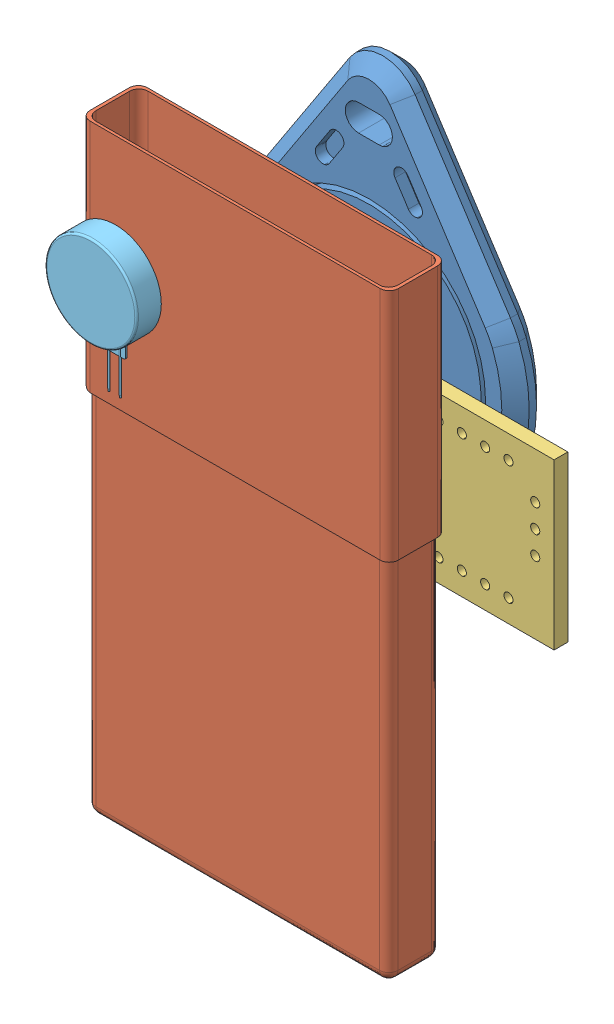
SolidWorks assembly 어셈블리1, configuration 기본. Lengths in mm.
Overall size (38.72 67.9 27.06).
5 component instances, 5 part files, 0 mates.
Components (placement in the parent):
- Tag_RFID_Arduino-1: Tag_RFID_Arduino [Valor predeterminado] at (-15.2122 -0.107 41.5697) size (32.05 41.57 3.8)
- battery-1: battery [Predeterminado] at (-27.7015 10.5413 56.1101) size (33.7 65.85 6.29)
- ArduinoProMini-1: ArduinoProMini [Predeterminado] at (-27.0155 -17.495 44.4281) size (34.5 18 1.5)
- hc05-1: hc05 [Varsayılan] at (-8.735 16.5437 54.3275) x (0.030342 -0.998477 -0.046081) z (0.087869 0.048589 -0.994946) size (42.6 16.1 5.9)
- 310-103 Precision Microdrive Haptic Motor-1: 310-103 Precision Microdrive Haptic Motor [Default] at (-22.3258 11.894 64.0328) size (10 15.99 2.7)
